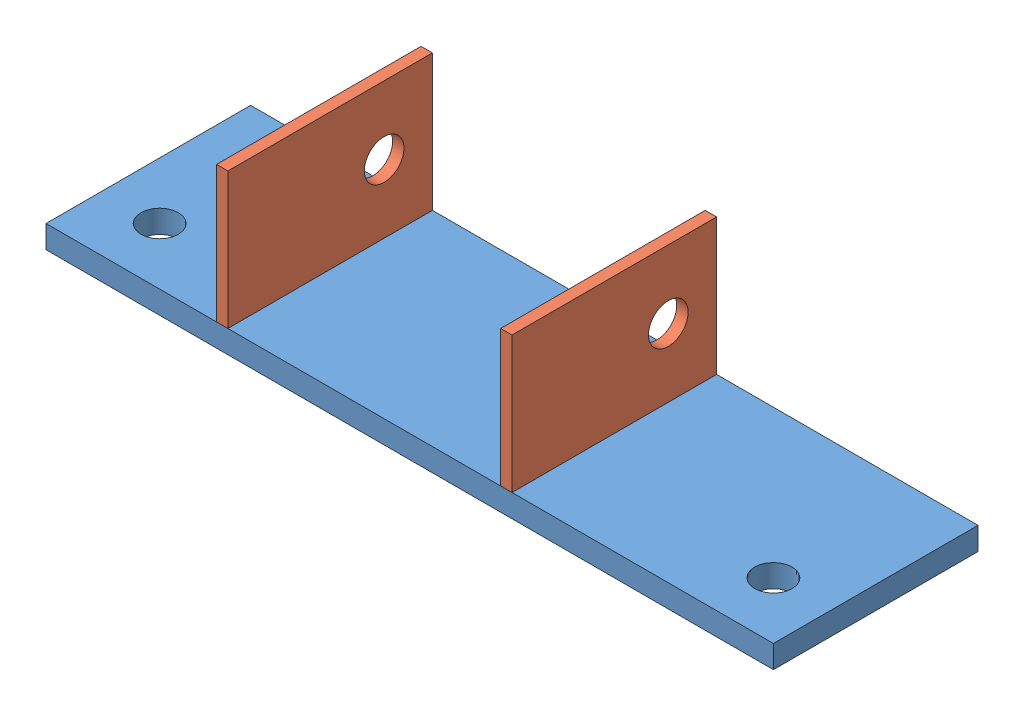
SolidWorks assembly Cam_Support_Ass_2, configuration Default. Lengths in mm.
Overall size (447.04 89.53 152.4).
3 component instances, 2 part files, 6 mates.
Components (placement in the parent):
- 01-020-00-0-1: 01-020-00-0 [Default] at (-221.5578 -37.3604 106.9552) size (447.04 13.97 152.4)
- Cam Support Tab-1: Cam Support Tab [Default] at (-126.3078 -24.6604 106.9552) x (0 1 0) z (-1 0 0) size (76.2 114.3 6.35)
- Cam Support Tab-3: Cam Support Tab [Default] at (32.4422 -24.6604 106.9552) x (0 1 0) z (-1 0 0) size (76.2 114.3 6.35)
Mates (geometry in assembly coordinates):
- Coincident6: coincident anti-aligned: plane of 01-020-00-0-1 through (-221.5578 -24.6604 -7.3448) normal (0 1 0); plane of Cam Support Tab-1 through (-126.3078 -24.6604 -7.3448) normal (0 -1 0)
- Coincident7: coincident aligned: line of 01-020-00-0-1 through (184.8422 -24.6604 -7.3448) axis (-1 0 0); line of Cam Support Tab-1 through (-119.9578 -24.6604 -7.3448) axis (-1 0 0)
- Distance1: distance = 95.25 mm: line of Cam Support Tab-1 through (-126.3078 -24.6604 -7.3448) axis (0 0 1); line of 01-020-00-0-1 through (-221.5578 -24.6604 -7.3448) axis (0 0 1)
- Coincident8: coincident anti-aligned: plane of 01-020-00-0-1 through (-221.5578 -24.6604 -7.3448) normal (0 1 0); plane of Cam Support Tab-3 through (32.4422 -24.6604 -7.3448) normal (0 -1 0)
- Coincident9: coincident aligned: plane of 01-020-00-0-1 through (-221.5578 -24.6604 -7.3448) normal (0 0 -1); plane of Cam Support Tab-3 through (32.4422 -24.6604 -7.3448) normal (0 0 -1)
- Distance3: distance = 152.4 mm anti-aligned: plane of Cam Support Tab-3 through (32.4422 -24.6604 -7.3448) normal (-1 0 0); plane of Cam Support Tab-1 through (-119.9578 -24.6604 -7.3448) normal (1 0 0)
